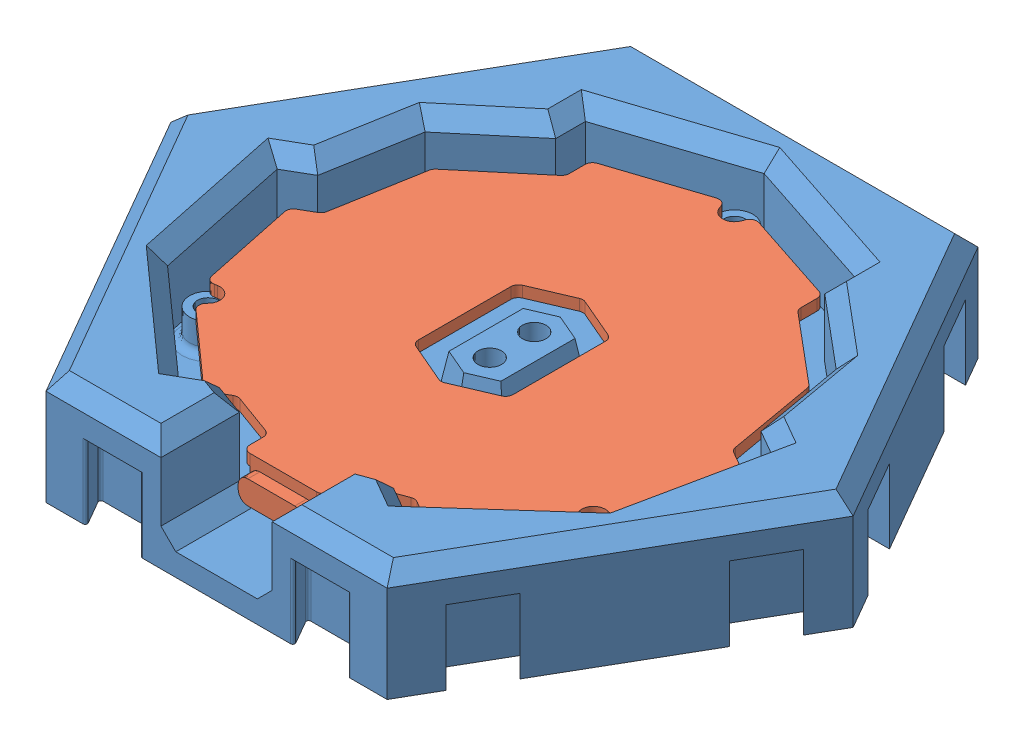
SolidWorks assembly PCB_Assem, configuration Default. Lengths in mm.
Overall size (92 15 79.67).
2 component instances, 2 part files, 4 mates.
Components (placement in the parent):
- Base-1: Base [Default] at (5.6115 30.1812 97.8911) size (92 15 79.67)
- PCB-1: PCB [Default] at (5.6115 39.1812 97.8911) x (1 0 0) z (0 1 0) size (60.81 62.93 4.67)
Mates (geometry in assembly coordinates):
- InPlace1: in place: plane of Base-1 through (28.6115 38.1812 28.054) normal (0 1 0); plane of ? through (0 38.1812 0) normal (0 1 0); moOrthogonalPlaneRef_w of Base-1 through (28.6115 38.1812 28.054) normal (0 1 0); plane of ? through (0 38.1812 0) normal (0 0 -1); plane of Base-1 through (28.6115 38.1812 28.054) normal (0 1 0); plane of ? through (0 38.1812 0) normal (1 0 0); plane of Base-1 through (28.6115 39.1812 28.054) normal (0 1 0); unknown of PCB-1
- Coincident1: coincident aligned: plane of Base-1; plane of PCB-1
- Coincident2: coincident aligned: moOrthogonalPlaneRef_w of Base-1 through (5.6115 39.1812 97.8911) normal (0 0 -1); plane of PCB-1 through (5.6115 39.1812 97.8911) normal (0 0 -1)
- Coincident3: coincident anti-aligned: moOrthogonalPlaneRef_w of Base-1 through (5.6115 39.1812 97.8911) normal (-1 0 0); plane of PCB-1 through (5.6115 39.1812 97.8911) normal (1 0 0)
